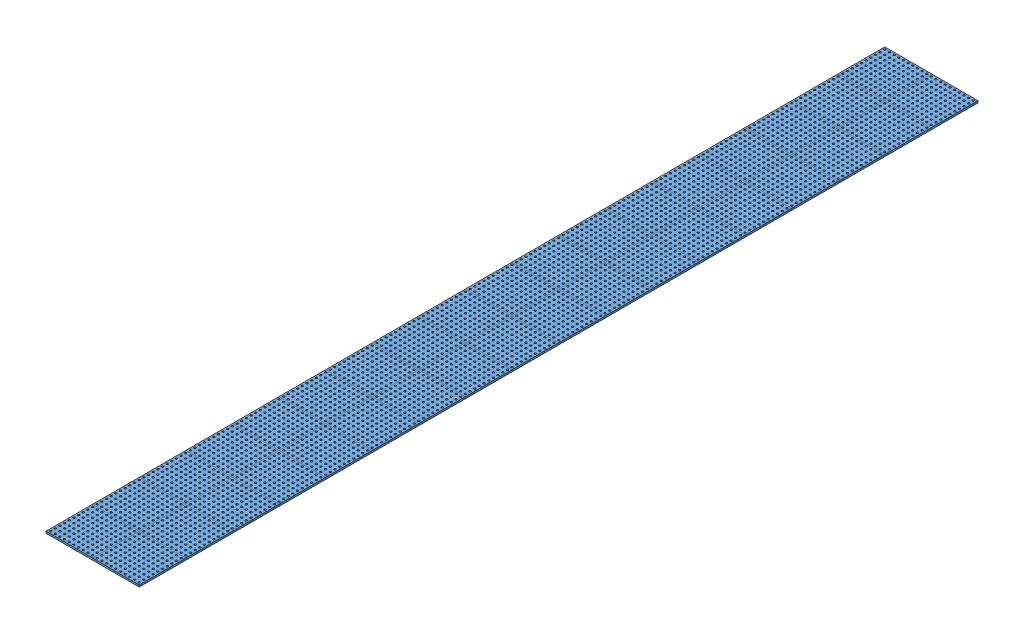
SolidWorks assembly Plataforma, configuration Valor predeterminado. Lengths in mm.
Overall size (1000 20 9000).
36 component instances, 1 part files, 0 mates.
Components (placement in the parent):
- Base_Furada-1: Base_Furada [Valor predeterminado] at origin size (500 20 500)
- Base_Furada-2: Base_Furada [Valor predeterminado] at (500 0 0) size (500 20 500)
- Base_Furada-3: Base_Furada [Valor predeterminado] at (0 0 -500) size (500 20 500)
- Base_Furada-4: Base_Furada [Valor predeterminado] at (500 0 -500) size (500 20 500)
- Base_Furada-5: Base_Furada [Valor predeterminado] at (0 0 1000) size (500 20 500)
- Base_Furada-6: Base_Furada [Valor predeterminado] at (0 0 2000) size (500 20 500)
- Base_Furada-7: Base_Furada [Valor predeterminado] at (0 0 3000) size (500 20 500)
- Base_Furada-8: Base_Furada [Valor predeterminado] at (0 0 4000) size (500 20 500)
- Base_Furada-9: Base_Furada [Valor predeterminado] at (0 0 5000) size (500 20 500)
- Base_Furada-10: Base_Furada [Valor predeterminado] at (0 0 6000) size (500 20 500)
- Base_Furada-11: Base_Furada [Valor predeterminado] at (0 0 7000) size (500 20 500)
- Base_Furada-22: Base_Furada [Valor predeterminado] at (0 0 500) size (500 20 500)
- Base_Furada-23: Base_Furada [Valor predeterminado] at (0 0 1500) size (500 20 500)
- Base_Furada-24: Base_Furada [Valor predeterminado] at (0 0 2500) size (500 20 500)
- Base_Furada-25: Base_Furada [Valor predeterminado] at (0 0 3500) size (500 20 500)
- Base_Furada-26: Base_Furada [Valor predeterminado] at (0 0 4500) size (500 20 500)
- Base_Furada-27: Base_Furada [Valor predeterminado] at (0 0 5500) size (500 20 500)
- Base_Furada-28: Base_Furada [Valor predeterminado] at (0 0 6500) size (500 20 500)
- Base_Furada-39: Base_Furada [Valor predeterminado] at (500 0 500) size (500 20 500)
- Base_Furada-40: Base_Furada [Valor predeterminado] at (500 0 1500) size (500 20 500)
- Base_Furada-41: Base_Furada [Valor predeterminado] at (500 0 2500) size (500 20 500)
- Base_Furada-42: Base_Furada [Valor predeterminado] at (500 0 3500) size (500 20 500)
- Base_Furada-43: Base_Furada [Valor predeterminado] at (500 0 4500) size (500 20 500)
- Base_Furada-44: Base_Furada [Valor predeterminado] at (500 0 5500) size (500 20 500)
- Base_Furada-45: Base_Furada [Valor predeterminado] at (500 0 6500) size (500 20 500)
- Base_Furada-56: Base_Furada [Valor predeterminado] at (500 0 1000) size (500 20 500)
- Base_Furada-57: Base_Furada [Valor predeterminado] at (500 0 2000) size (500 20 500)
- Base_Furada-58: Base_Furada [Valor predeterminado] at (500 0 3000) size (500 20 500)
- Base_Furada-59: Base_Furada [Valor predeterminado] at (500 0 4000) size (500 20 500)
- Base_Furada-60: Base_Furada [Valor predeterminado] at (500 0 5000) size (500 20 500)
- Base_Furada-61: Base_Furada [Valor predeterminado] at (500 0 6000) size (500 20 500)
- Base_Furada-62: Base_Furada [Valor predeterminado] at (500 0 7000) size (500 20 500)
- Base_Furada-73: Base_Furada [Valor predeterminado] at (500 0 8000) size (500 20 500)
- Base_Furada-74: Base_Furada [Valor predeterminado] at (500 0 7500) size (500 20 500)
- Base_Furada-75: Base_Furada [Valor predeterminado] at (0 0 7500) size (500 20 500)
- Base_Furada-76: Base_Furada [Valor predeterminado] at (0 0 8000) size (500 20 500)
